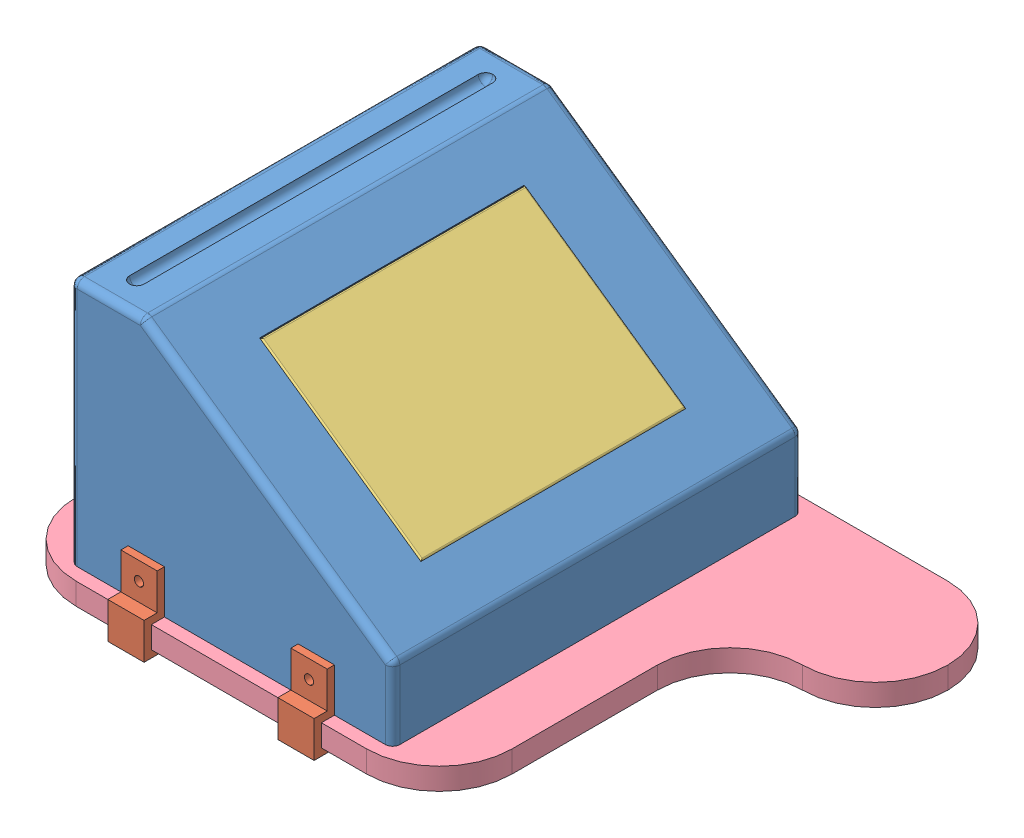
SolidWorks assembly TouchAsm, configuration Default. Lengths in mm.
Overall size (400 190.45 310).
5 component instances, 4 part files, 9 mates.
Components (placement in the parent):
- BaseTouch-1: BaseTouch [Default] at (188.7894 159.0961 164.2763) size (222.02 170.45 282)
- Agarre-1: Agarre [Default] at (123.7894 124.0961 305.2763) x (0 0 -1) z (1 0 0) size (310 50 25)
- Agarre-2: Agarre [Default] at (6.7675 124.0961 305.2763) x (0 0 -1) z (1 0 0) size (310 50 25)
- Tablet-1: Tablet [Default] at (98.4077 212.6159 305.2763) x (0 0 -1) z (0.819152 -0.573576 0) size (182 9 135)
- Paleta-1: Paleta [Default] at (229.9713 109.0961 155.2763) x (0 0 1) z (1 0 0) size (300 15 400)
Mates (geometry in assembly coordinates):
- Coincident8: coincident anti-aligned: plane of BaseTouch-1 through (188.7894 159.0961 446.2763) normal (0 0 1); plane of Agarre-2 through (31.7675 124.0961 446.2763) normal (0 0 -1)
- Concentric3: concentric aligned: circle of BaseTouch-1; circle of Agarre-2
- Coincident10: coincident anti-aligned: plane of BaseTouch-1 through (188.7894 159.0961 446.2763) normal (0 0 1); plane of Agarre-1 through (148.7894 124.0961 446.2763) normal (0 0 -1)
- Coincident11: coincident anti-aligned: cylinder of BaseTouch-1; cylinder of Agarre-1 through (136.2894 126.5961 460.2763) axis (0 0 -1) radius 3.175
- Coincident13: coincident anti-aligned: plane of BaseTouch-1 through (184.2008 152.5429 164.2763) normal (0.573576 0.819152 0); plane of Tablet-1 through (98.4077 212.6159 305.2763) normal (-0.573576 -0.819152 0)
- Coincident15: coincident aligned: line of BaseTouch-1 through (158.289 180.4527 214.2763) axis (0 0 1); line of Tablet-1 through (158.289 180.4527 214.2763) axis (0 0 1)
- Coincident16: coincident anti-aligned: line of BaseTouch-1 through (47.2678 258.1906 396.2763) axis (0.819152 -0.573576 0); line of Tablet-1 through (158.289 180.4527 396.2763) axis (-0.819152 0.573576 0)
- Coincident17: coincident anti-aligned: plane of BaseTouch-1 through (188.7894 109.0961 446.2763) normal (0 -1 0); plane of Paleta-1 through (229.9713 109.0961 155.2763) normal (0 1 0)
- Coincident19: coincident anti-aligned: plane of Agarre-1 through (148.7894 124.0961 155.2763) normal (0 0 1); plane of Paleta-1 through (229.9713 94.0961 155.2763) normal (0 0 -1)
